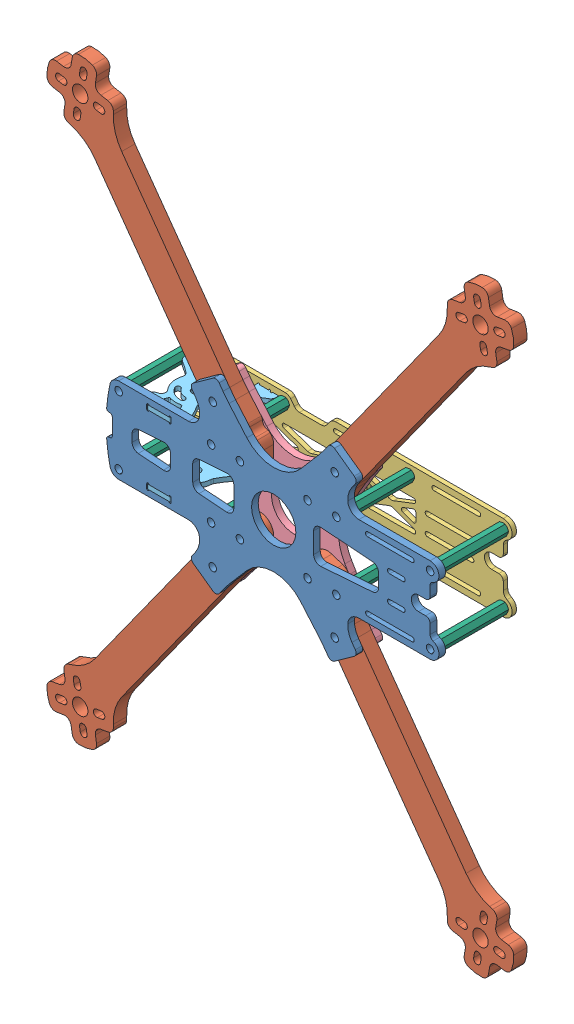
SolidWorks assembly SOURCE_ONE_ASSEM, configuration Default. Lengths in mm.
Overall size (217.15 276.09 35).
17 component instances, 6 part files, 15 mates.
Components (placement in the parent):
- Source_One_v.0.1.1_Bottom_Plate-1: Source_One_v.0.1.1_Bottom_Plate [Default] x (-1 0 0) z (0 0 -1) size (149.92 83.97 3)
- Source_One_v.0.1.1_Arm-1: Source_One_v.0.1.1_Arm [Default] at (-90.303 119.7721 -3) x (-0.583266 0.812281 0) z (0 0 -1) size (148.02 26.19 6)
- Source_One_v.0.1.1_Top_Plate-1: Source_One_v.0.1.1_Top_Plate [Default] at (1 0 -33) x (1 0 0) z (0 0 -1) size (148.51 38.5 2)
- Source_One_v.0.1.1_Arm_Retainment_Block-1: Source_One_v.0.1.1_Arm_Retainment_Block [Default] at (0 0 -9) x (0 -1 0) z (0 0 -1) size (83.97 74.35 3)
- Source_One_v.0.1.1_Cam_Brace-1: Source_One_v.0.1.1_Cam_Brace [Default] at (-51.3508 -16.5 -16.3612) x (0 0 -1) z (0 1 0) size (35 36.7 2)
- Source_One_v.0.1.1_Cam_Brace-2: Source_One_v.0.1.1_Cam_Brace [Default] at (-51.3508 14.5 -16.3612) x (0 0 -1) z (0 1 0) size (35 36.7 2)
- ALUM_THRDED_STANDOFF_M3-8: ALUM_THRDED_STANDOFF_M3 [94868A729] at (70.5603 15.25 -18) x (-0.918253 0.395993 0) z (0 0 -1) size (4.5 5.2 30.67)
- ALUM_THRDED_STANDOFF_M3-10: ALUM_THRDED_STANDOFF_M3 [94868A729] at (28.2503 15.25 -18) x (-0.918253 0.395993 0) z (0 0 -1) size (4.5 5.2 30.67)
- ALUM_THRDED_STANDOFF_M3-11: ALUM_THRDED_STANDOFF_M3 [94868A729] at (70.5603 -15.25 -18) x (-0.918253 0.395993 0) z (0 0 -1) size (4.5 5.2 30.67)
- ALUM_THRDED_STANDOFF_M3-12: ALUM_THRDED_STANDOFF_M3 [94868A729] at (28.2503 -15.25 -18) x (-0.918253 0.395993 0) z (0 0 -1) size (4.5 5.2 30.67)
- ALUM_THRDED_STANDOFF_M3-13: ALUM_THRDED_STANDOFF_M3 [94868A729] at (-28.2497 15.25 -18) x (-0.918253 0.395993 0) z (0 0 -1) size (4.5 5.2 30.67)
- ALUM_THRDED_STANDOFF_M3-14: ALUM_THRDED_STANDOFF_M3 [94868A729] at (-28.2497 -15.25 -18) x (-0.918253 0.395993 0) z (0 0 -1) size (4.5 5.2 30.67)
- ALUM_THRDED_STANDOFF_M3-15: ALUM_THRDED_STANDOFF_M3 [94868A729] at (-69.9497 15.25 -18) x (-0.918253 0.395993 0) z (0 0 -1) size (4.5 5.2 30.67)
- ALUM_THRDED_STANDOFF_M3-16: ALUM_THRDED_STANDOFF_M3 [94868A729] at (-69.9497 -15.25 -18) x (-0.918253 0.395993 0) z (0 0 -1) size (4.5 5.2 30.67)
- Source_One_v.0.1.1_Arm-7: Source_One_v.0.1.1_Arm [Default] at (90.303 119.7721 -9) x (0.583266 0.812281 0) z (0 0 1) size (148.02 26.19 6)
- Source_One_v.0.1.1_Arm-8: Source_One_v.0.1.1_Arm [Default] at (90.303 -119.7721 -3) x (0.583266 -0.812281 0) z (0 0 -1) size (148.02 26.19 6)
- Source_One_v.0.1.1_Arm-9: Source_One_v.0.1.1_Arm [Default] at (-90.303 -119.7721 -9) x (-0.583266 -0.812281 0) z (0 0 1) size (148.02 26.19 6)
Mates (geometry in assembly coordinates):
- Coincident1: coincident aligned: circle of Source_One_v.0.1.1_Bottom_Plate-1; circle of Source_One_v.0.1.1_Arm-1
- Concentric2: concentric aligned: cylinder of Source_One_v.0.1.1_Bottom_Plate-1 through (-27.4986 32.3079 -3) axis (0 0 -1) radius 1.7; cylinder of Source_One_v.0.1.1_Arm-1 through (-27.4986 32.3079 -9) axis (0 0 -1) radius 1.7
- Concentric5: concentric aligned: cylinder of Source_One_v.0.1.1_Arm_Retainment_Block-1 through (-27.4986 32.3079 -12) axis (0 0 -1) radius 2.25; cylinder of Source_One_v.0.1.1_Arm-1 through (-27.4986 32.3079 -9) axis (0 0 -1) radius 1.7
- Coincident7: coincident anti-aligned: plane of Source_One_v.0.1.1_Bottom_Plate-1 through (-47.2807 -14.5 -3) normal (0 -1 0); plane of Source_One_v.0.1.1_Cam_Brace-1 through (-34.8681 -14.5 -34.5) normal (0 1 0)
- Coincident8: coincident anti-aligned: plane of Source_One_v.0.1.1_Bottom_Plate-1 through (-26.239 -39.9834 -3) normal (0 0 -1); plane of Source_One_v.0.1.1_Cam_Brace-1 through (-62.2807 -14.5 -3) normal (0 0 1)
- Coincident9: coincident anti-aligned: plane of Source_One_v.0.1.1_Bottom_Plate-1 through (-57.2807 -14.5 -3) normal (1 0 0); plane of Source_One_v.0.1.1_Cam_Brace-1 through (-57.2807 -14.5 -3) normal (-1 0 0)
- Coincident10: coincident anti-aligned: plane of Source_One_v.0.1.1_Bottom_Plate-1 through (-56.2807 16.5 -3) normal (0 -1 0); plane of Source_One_v.0.1.1_Cam_Brace-2 through (-34.8681 16.5 -34.5) normal (0 1 0)
- Coincident11: coincident anti-aligned: plane of Source_One_v.0.1.1_Bottom_Plate-1 through (-26.239 -39.9834 -3) normal (0 0 -1); plane of Source_One_v.0.1.1_Cam_Brace-2 through (-62.2807 16.5 -3) normal (0 0 1)
- Coincident12: coincident anti-aligned: plane of Source_One_v.0.1.1_Bottom_Plate-1 through (-57.2807 14.5 -3) normal (1 0 0); plane of Source_One_v.0.1.1_Cam_Brace-2 through (-57.2807 16.5 -3) normal (-1 0 0)
- Concentric14: concentric anti-aligned: circle of Source_One_v.0.1.1_Bottom_Plate-1; circle of ALUM_THRDED_STANDOFF_M3-8
- Coincident18: coincident anti-aligned: plane of Source_One_v.0.1.1_Bottom_Plate-1 through (-26.239 -39.9834 -3) normal (0 0 -1); plane of ALUM_THRDED_STANDOFF_M3-8 through (71.5892 17.6357 -3) normal (0 0 1)
- Concentric19: concentric anti-aligned: circle of Source_One_v.0.1.1_Top_Plate-1; circle of ALUM_THRDED_STANDOFF_M3-8
- Coincident22: coincident anti-aligned: plane of Source_One_v.0.1.1_Arm-1 through (-20.5662 15.7239 -9) normal (0 0 -1); plane of Source_One_v.0.1.1_Arm_Retainment_Block-1 through (26.5666 19.9581 -9) normal (0 0 1)
- Concentric20: concentric anti-aligned: circle of Source_One_v.0.1.1_Top_Plate-1; circle of ALUM_THRDED_STANDOFF_M3-8
- Coincident292: coincident anti-aligned: plane of Source_One_v.0.1.1_Top_Plate-1 through (-27.7512 -16.25 -33) normal (0 0 1); plane of ALUM_THRDED_STANDOFF_M3-8 through (71.5892 17.6357 -33) normal (0 0 -1)
